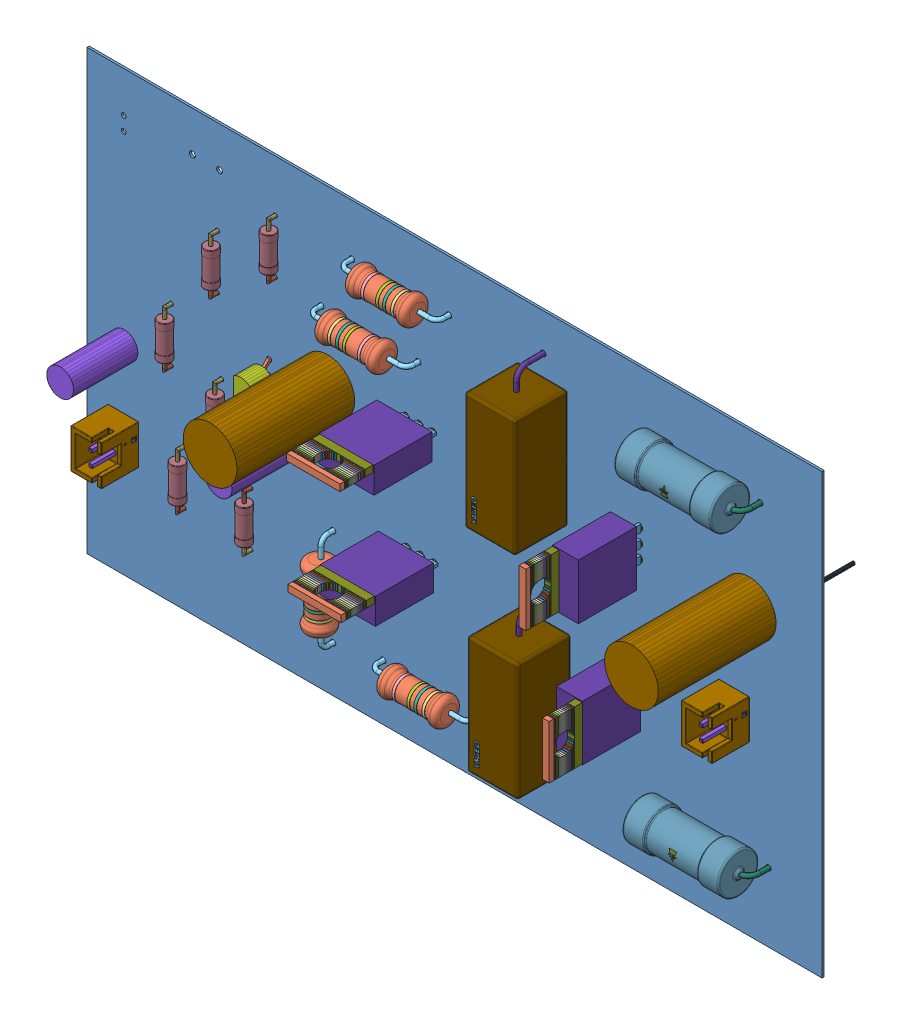
SolidWorks assembly PCB1, configuration Default. Lengths in mm.
Overall size (137.29 81.92 39).
464 component instances, 65 part files, 0 mates.
Components (placement in the parent):
- PCB1.step-1: PCB1.step [Default] at origin size (137.29 81.92 39)
  - Board.step-1: Board.step [Default] at origin size (137.29 81.92 0.41)
    - Open CASCADE STEP translator 6.8 1.1.1.step-1: Open CASCADE STEP translator 6.8 1.1.1.step [Default] at (0 0 -0.4115) size (137.29 81.92 0.41)
  - R61.step-1: R61.step [Default] at origin size (18.91 5.72 7.96)
    - Res_Yageo_KNP100JR-73-22R_eec.step-1: Res_Yageo_KNP100JR-73-22R_eec.step [Default] at (64.389 10.414 0) x (-1 0 0) z (0 0 1) size (18.91 5.72 7.96)
      - 1.step-1: 1.step [Default] at (0 0 2.55) size (11.5 5.1 5.1)
      - 2.step-1: 2.step [Default] at (-3.2931 0 2.55) x (0 0 -1) z (1 0 0) size (4.2 4.2 0.5)
      - 3.step-1: 3.step [Default] at (2.7931 0 2.55) x (0 -0.492137 0.870518) z (-1 0 0) size (4.2 4.2 0.5)
      - 4.step-1: 4.step [Default] at (0 0 -2.55) size (18.91 0.8 5.21)
      - 5.step-1: 5.step [Default] at (-1.7931 0 2.55) x (0 0 -1) z (1 0 0) size (4.2 4.2 0.5)
      - 6.step-1: 6.step [Default] at (0.0069 0 2.55) x (0 -0.017206 0.999852) z (-1 0 0) size (4.2 4.2 0.5)
  - R51.step-1: R51.step [Default] at origin size (18.91 5.72 7.96)
    - Res_Yageo_KNP100JR-73-22R_eec.step-1: Res_Yageo_KNP100JR-73-22R_eec.step [Default] at (52.832 61.976 0) x (1 0 0) z (0 0 1) size (18.91 5.72 7.96)
      - 1.step-1: 1.step [Default] at (0 0 2.55) size (11.5 5.1 5.1)
      - 2.step-1: 2.step [Default] at (-3.2931 0 2.55) x (0 0 -1) z (1 0 0) size (4.2 4.2 0.5)
      - 3.step-1: 3.step [Default] at (2.7931 0 2.55) x (0 -0.492137 0.870518) z (-1 0 0) size (4.2 4.2 0.5)
      - 4.step-1: 4.step [Default] at (0 0 -2.55) size (18.91 0.8 5.21)
      - 5.step-1: 5.step [Default] at (-1.7931 0 2.55) x (0 0 -1) z (1 0 0) size (4.2 4.2 0.5)
      - 6.step-1: 6.step [Default] at (0.0069 0 2.55) x (0 -0.017206 0.999852) z (-1 0 0) size (4.2 4.2 0.5)
  - output.step-1: output.step [Default] at origin size (5.75 7.4 10.4)
    - Conn_JST_B2B-XH-A_LF_SN_eec.step-1: Conn_JST_B2B-XH-A_LF_SN_eec.step [Default] at (120.887 35.072 0) x (0 -1 0) z (0 0 1) size (7.4 5.75 10.4)
      - 1-0.step-1: 1-0.step [Default] at (0 0.025 0) x (-1 0 0) z (0 1 0) size (7.4 10.4 5.75)
        - 1-1.step-1: 1-1.step [Default] at origin size (3.14 10.2 0.64)
        - B2B-XH-A.step-1: B2B-XH-A.step [Default] at origin size (7.4 7 5.75)
        - JST_Logo_adjustable.step-1: JST_Logo_adjustable.step [Default] at (-1.7267 5.5034 2.841) size (0.85 2.3 0.01)
  - input.step-1: input.step [Default] at origin size (5.75 7.4 10.4)
    - Conn_JST_B2B-XH-A_LF_SN_eec.step-1: Conn_JST_B2B-XH-A_LF_SN_eec.step [Default] at (6.841 22.499 0) x (0 -1 0) z (0 0 1) size (7.4 5.75 10.4)
      - 1-0.step-1: 1-0.step [Default] at (0 0.025 0) x (-1 0 0) z (0 1 0) size (7.4 10.4 5.75)
        - 1-1.step-1: 1-1.step [Default] at origin size (3.14 10.2 0.64)
        - B2B-XH-A.step-1: B2B-XH-A.step [Default] at origin size (7.4 7 5.75)
        - JST_Logo_adjustable.step-1: JST_Logo_adjustable.step [Default] at (-1.7267 5.5034 2.841) size (0.85 2.3 0.01)
  - RE.step-1: RE.step [Default] at origin size (2.5 10.6 6.5)
    - Res_Vishay_BC_Components_MRS25000C1101FCT00_eec.step-1: Res_Vishay_BC_Components_MRS25000C1101FCT00_eec.step [Default] at (30.607 20.955 0) x (0 -1 0) z (0 0 1) size (2.05 0.6 5.55)
    - Res_Vishay_BC_Components_MRS25000C1101FCT00_eec-2.step-1: Res_Vishay_BC_Components_MRS25000C1101FCT00_eec-2.step [Default] at (30.607 20.955 0) x (0 -1 0) z (0 0 1) size (2.05 0.6 5.55)
    - Res_Vishay_BC_Components_MRS25000C1101FCT00_eec-3.step-1: Res_Vishay_BC_Components_MRS25000C1101FCT00_eec-3.step [Default] at (30.607 20.955 0) x (0 -1 0) z (0 0 1) size (6.5 2.5 2.5)
  - RC.step-1: RC.step [Default] at origin size (2.5 10.6 6.5)
    - Res_Vishay_BC_Components_MRS25000C1101FCT00_eec.step-1: Res_Vishay_BC_Components_MRS25000C1101FCT00_eec.step [Default] at (35.179 67.31 0) x (0 1 0) z (0 0 1) size (2.05 0.6 5.55)
    - Res_Vishay_BC_Components_MRS25000C1101FCT00_eec-2.step-1: Res_Vishay_BC_Components_MRS25000C1101FCT00_eec-2.step [Default] at (35.179 67.31 0) x (0 1 0) z (0 0 1) size (2.05 0.6 5.55)
    - Res_Vishay_BC_Components_MRS25000C1101FCT00_eec-3.step-1: Res_Vishay_BC_Components_MRS25000C1101FCT00_eec-3.step [Default] at (35.179 67.31 0) x (0 1 0) z (0 0 1) size (6.5 2.5 2.5)
  - R10.step-1: R10.step [Default] at origin size (22.46 7.5 11.5)
    - Res_Vishay_AC05000003909JAC00_eec.step-1: Res_Vishay_AC05000003909JAC00_eec.step [Default] at (116.459 12.827 0) size (22.46 7.5 11.5)
      - AC0500000XXXJAC00.step-1: AC0500000XXXJAC00.step [Default] at (-37 0 3.75) size (18.87 7.5 7.5)
      - 1-4.step-1: 1-4.step [Default] at (0 0 -8) x (1 0 0) z (0 -1 0) size (22.46 8.15 0.8)
      - 2-5.step-1: 2-5.step [Default] at (-37 0 3.75) size (1.63 1.9 3.41)
  - R9.step-1: R9.step [Default] at origin size (22.46 7.5 11.5)
    - Res_Vishay_AC05000003909JAC00_eec.step-1: Res_Vishay_AC05000003909JAC00_eec.step [Default] at (114.935 71.12 0) x (-1 0 0) z (0 0 1) size (22.46 7.5 11.5)
      - AC0500000XXXJAC00.step-1: AC0500000XXXJAC00.step [Default] at (-37 0 3.75) size (18.87 7.5 7.5)
      - 1-4.step-1: 1-4.step [Default] at (0 0 -8) x (1 0 0) z (0 -1 0) size (22.46 8.15 0.8)
      - 2-5.step-1: 2-5.step [Default] at (-37 0 3.75) size (1.63 1.9 3.41)
  - R8.step-1: R8.step [Default] at origin size (9.5 29.91 14)
    - Res_Yageo_SQP500JB-1R2_eec.step-1: Res_Yageo_SQP500JB-1R2_eec.step [Default] at (85.217 60.452 0) x (0 1 0) z (0 0 1) size (29.91 9.5 14)
      - 1-6.step-1: 1-6.step [Default] at origin size (29.91 0.8 9.4)
      - 2-7.step-1: 2-7.step [Default] at origin size (22 9.5 10)
      - Yageo_Logo.step-1: Yageo_Logo.step [Default] at (-8.1443 3.6121 9.991) size (4.52 1.05 0.01)
  - R7.step-1: R7.step [Default] at origin size (9.5 29.91 14)
    - Res_Yageo_SQP500JB-1R2_eec.step-1: Res_Yageo_SQP500JB-1R2_eec.step [Default] at (85.725 21.209 0) x (0 1 0) z (0 0 1) size (29.91 9.5 14)
      - 1-6.step-1: 1-6.step [Default] at origin size (29.91 0.8 9.4)
      - 2-7.step-1: 2-7.step [Default] at origin size (22 9.5 10)
      - Yageo_Logo.step-1: Yageo_Logo.step [Default] at (-8.1443 3.6121 9.991) size (4.52 1.05 0.01)
  - R6.step-1: R6.step [Default] at origin size (5.72 18.91 7.96)
    - Res_Yageo_KNP100JR-73-22R_eec.step-1: Res_Yageo_KNP100JR-73-22R_eec.step [Default] at (45.974 17.653 0) x (0 1 0) z (0 0 1) size (18.91 5.72 7.96)
      - 1.step-1: 1.step [Default] at (0 0 2.55) size (11.5 5.1 5.1)
      - 2.step-1: 2.step [Default] at (-3.2931 0 2.55) x (0 0 -1) z (1 0 0) size (4.2 4.2 0.5)
      - 3.step-1: 3.step [Default] at (2.7931 0 2.55) x (0 -0.492137 0.870518) z (-1 0 0) size (4.2 4.2 0.5)
      - 4.step-1: 4.step [Default] at (0 0 -2.55) size (18.91 0.8 5.21)
      - 5.step-1: 5.step [Default] at (-1.7931 0 2.55) x (0 0 -1) z (1 0 0) size (4.2 4.2 0.5)
      - 6.step-1: 6.step [Default] at (0.0069 0 2.55) x (0 -0.017206 0.999852) z (-1 0 0) size (4.2 4.2 0.5)
  - R5.step-1: R5.step [Default] at origin size (18.91 5.72 7.96)
    - Res_Yageo_KNP100JR-73-22R_eec.step-1: Res_Yageo_KNP100JR-73-22R_eec.step [Default] at (58.547 72.39 0) x (-1 0 0) z (0 0 1) size (18.91 5.72 7.96)
      - 1.step-1: 1.step [Default] at (0 0 2.55) size (11.5 5.1 5.1)
      - 2.step-1: 2.step [Default] at (-3.2931 0 2.55) x (0 0 -1) z (1 0 0) size (4.2 4.2 0.5)
      - 3.step-1: 3.step [Default] at (2.7931 0 2.55) x (0 -0.492137 0.870518) z (-1 0 0) size (4.2 4.2 0.5)
      - 4.step-1: 4.step [Default] at (0 0 -2.55) size (18.91 0.8 5.21)
      - 5.step-1: 5.step [Default] at (-1.7931 0 2.55) x (0 0 -1) z (1 0 0) size (4.2 4.2 0.5)
      - 6.step-1: 6.step [Default] at (0.0069 0 2.55) x (0 -0.017206 0.999852) z (-1 0 0) size (4.2 4.2 0.5)
  - R4.step-1: R4.step [Default] at origin size (2.5 10.6 6.5)
    - Res_Vishay_BC_Components_MRS25000C1101FCT00_eec.step-1: Res_Vishay_BC_Components_MRS25000C1101FCT00_eec.step [Default] at (18.161 21.463 0) x (0 1 0) z (0 0 1) size (2.05 0.6 5.55)
    - Res_Vishay_BC_Components_MRS25000C1101FCT00_eec-2.step-1: Res_Vishay_BC_Components_MRS25000C1101FCT00_eec-2.step [Default] at (18.161 21.463 0) x (0 1 0) z (0 0 1) size (2.05 0.6 5.55)
    - Res_Vishay_BC_Components_MRS25000C1101FCT00_eec-3.step-1: Res_Vishay_BC_Components_MRS25000C1101FCT00_eec-3.step [Default] at (18.161 21.463 0) x (0 1 0) z (0 0 1) size (6.5 2.5 2.5)
  - R3.step-1: R3.step [Default] at origin size (2.5 10.6 6.5)
    - Res_Vishay_BC_Components_MRS25000C1101FCT00_eec.step-1: Res_Vishay_BC_Components_MRS25000C1101FCT00_eec.step [Default] at (25.146 35.814 0) x (0 1 0) z (0 0 1) size (2.05 0.6 5.55)
    - Res_Vishay_BC_Components_MRS25000C1101FCT00_eec-2.step-1: Res_Vishay_BC_Components_MRS25000C1101FCT00_eec-2.step [Default] at (25.146 35.814 0) x (0 1 0) z (0 0 1) size (2.05 0.6 5.55)
    - Res_Vishay_BC_Components_MRS25000C1101FCT00_eec-3.step-1: Res_Vishay_BC_Components_MRS25000C1101FCT00_eec-3.step [Default] at (25.146 35.814 0) x (0 1 0) z (0 0 1) size (6.5 2.5 2.5)
  - R2.step-1: R2.step [Default] at origin size (2.5 10.6 6.5)
    - Res_Vishay_BC_Components_MRS25000C1101FCT00_eec.step-1: Res_Vishay_BC_Components_MRS25000C1101FCT00_eec.step [Default] at (24.384 59.436 0) x (0 1 0) z (0 0 1) size (2.05 0.6 5.55)
    - Res_Vishay_BC_Components_MRS25000C1101FCT00_eec-2.step-1: Res_Vishay_BC_Components_MRS25000C1101FCT00_eec-2.step [Default] at (24.384 59.436 0) x (0 1 0) z (0 0 1) size (2.05 0.6 5.55)
    - Res_Vishay_BC_Components_MRS25000C1101FCT00_eec-3.step-1: Res_Vishay_BC_Components_MRS25000C1101FCT00_eec-3.step [Default] at (24.384 59.436 0) x (0 1 0) z (0 0 1) size (6.5 2.5 2.5)
  - R1.step-1: R1.step [Default] at origin size (2.5 10.6 6.5)
    - Res_Vishay_BC_Components_MRS25000C1101FCT00_eec.step-1: Res_Vishay_BC_Components_MRS25000C1101FCT00_eec.step [Default] at (15.748 43.307 0) x (0 1 0) z (0 0 1) size (2.05 0.6 5.55)
    - Res_Vishay_BC_Components_MRS25000C1101FCT00_eec-2.step-1: Res_Vishay_BC_Components_MRS25000C1101FCT00_eec-2.step [Default] at (15.748 43.307 0) x (0 1 0) z (0 0 1) size (2.05 0.6 5.55)
    - Res_Vishay_BC_Components_MRS25000C1101FCT00_eec-3.step-1: Res_Vishay_BC_Components_MRS25000C1101FCT00_eec-3.step [Default] at (15.748 43.307 0) x (0 1 0) z (0 0 1) size (6.5 2.5 2.5)
  - Q5.step-1: Q5.step [Default] at origin size (4.85 10.3 21.45)
    - 6100337184.step-1: 6100337184.step [Default] at (105.55 30.861 18.98) size (1.25 9.95 0.87)
      - Extruded.step-1: Extruded.step [Default] at origin size (1.25 9.95 0.87)
    - 6100336784.step-1: 6100336784.step [Default] at (105.55 27.411 17.05) size (1.25 3.05 0.38)
      - Extruded-8.step-1: Extruded-8.step [Default] at origin size (1.25 3.05 0.38)
    - 6100336784.step-2: 6100336784.step [Default] at (105.55 34.311 17.05) size (1.25 3.05 0.38)
      - Extruded-8.step-1: Extruded-8.step [Default] at origin size (1.25 3.05 0.38)
    - 6100335504.step-1: 6100335504.step [Default] at (105.55 27.411 16.67) size (1.25 3.05 0.38)
      - Extruded-9.step-1: Extruded-9.step [Default] at origin size (1.25 3.05 0.38)
    - 6100335504.step-2: 6100335504.step [Default] at (105.55 34.311 16.67) size (1.25 3.05 0.38)
      - Extruded-9.step-1: Extruded-9.step [Default] at origin size (1.25 3.05 0.38)
    - 6100342224.step-1: 6100342224.step [Default] at (105.55 27.4295 17.43) size (1.25 3.09 0.36)
      - Extruded-10.step-1: Extruded-10.step [Default] at origin size (1.25 3.09 0.36)
    - 6100342224.step-2: 6100342224.step [Default] at (105.55 34.2925 17.43) size (1.25 3.09 0.36)
      - Extruded-10.step-1: Extruded-10.step [Default] at origin size (1.25 3.09 0.36)
    - 6100331024.step-1: 6100331024.step [Default] at (105.55 27.4295 16.31) size (1.25 3.09 0.37)
      - Extruded-11.step-1: Extruded-11.step [Default] at origin size (1.25 3.09 0.37)
    - 6100331024.step-2: 6100331024.step [Default] at (105.55 34.2925 16.31) size (1.25 3.09 0.37)
      - Extruded-11.step-1: Extruded-11.step [Default] at origin size (1.25 3.09 0.37)
    - 6100330544.step-1: 6100330544.step [Default] at (105.55 27.4843 17.79) size (1.25 3.2 0.33)
      - Extruded-12.step-1: Extruded-12.step [Default] at origin size (1.25 3.2 0.33)
    - 6100330544.step-2: 6100330544.step [Default] at (105.55 34.2377 17.79) size (1.25 3.2 0.33)
      - Extruded-12.step-1: Extruded-12.step [Default] at origin size (1.25 3.2 0.33)
    - 6100330224.step-1: 6100330224.step [Default] at (105.55 27.4843 15.98) size (1.25 3.2 0.34)
      - Extruded-13.step-1: Extruded-13.step [Default] at origin size (1.25 3.2 0.34)
    - 6100330224.step-2: 6100330224.step [Default] at (105.55 34.2377 15.98) size (1.25 3.2 0.34)
      - Extruded-13.step-1: Extruded-13.step [Default] at origin size (1.25 3.2 0.34)
    - 6100325984.step-1: 6100325984.step [Default] at (105.55 27.5732 18.12) size (1.25 3.37 0.3)
      - Extruded-14.step-1: Extruded-14.step [Default] at origin size (1.25 3.37 0.3)
    - 6100325984.step-2: 6100325984.step [Default] at (105.55 34.1488 18.12) size (1.25 3.37 0.3)
      - Extruded-14.step-1: Extruded-14.step [Default] at origin size (1.25 3.37 0.3)
    - 6100325984.step-3: 6100325984.step [Default] at (105.55 27.5732 15.69) size (1.25 3.37 0.3)
      - Extruded-14.step-1: Extruded-14.step [Default] at origin size (1.25 3.37 0.3)
    - 6100325984.step-4: 6100325984.step [Default] at (105.55 34.1488 15.69) size (1.25 3.37 0.3)
      - Extruded-14.step-1: Extruded-14.step [Default] at origin size (1.25 3.37 0.3)
    - 6100325824.step-1: 6100325824.step [Default] at (105.55 27.6929 18.41) size (1.25 3.61 0.25)
      - Extruded-15.step-1: Extruded-15.step [Default] at origin size (1.25 3.61 0.25)
    - 6100325824.step-2: 6100325824.step [Default] at (105.55 34.0291 18.41) size (1.25 3.61 0.25)
      - Extruded-15.step-1: Extruded-15.step [Default] at origin size (1.25 3.61 0.25)
    - 6100326864.step-1: 6100326864.step [Default] at (105.55 27.6929 15.45) size (1.25 3.61 0.24)
      - Extruded-16.step-1: Extruded-16.step [Default] at origin size (1.25 3.61 0.24)
    - 6100326864.step-2: 6100326864.step [Default] at (105.55 34.0291 15.45) size (1.25 3.61 0.24)
      - Extruded-16.step-1: Extruded-16.step [Default] at origin size (1.25 3.61 0.24)
    - 6100326304.step-1: 6100326304.step [Default] at (105.55 27.8388 18.65) size (1.25 3.91 0.18)
      - Extruded-17.step-1: Extruded-17.step [Default] at origin size (1.25 3.91 0.18)
    - 6100326304.step-2: 6100326304.step [Default] at (105.55 33.8832 18.65) size (1.25 3.91 0.18)
      - Extruded-17.step-1: Extruded-17.step [Default] at origin size (1.25 3.91 0.18)
    - 6100326304.step-3: 6100326304.step [Default] at (105.55 27.8388 15.27) size (1.25 3.91 0.18)
      - Extruded-17.step-1: Extruded-17.step [Default] at origin size (1.25 3.91 0.18)
    - 6100326304.step-4: 6100326304.step [Default] at (105.55 33.8832 15.27) size (1.25 3.91 0.18)
      - Extruded-17.step-1: Extruded-17.step [Default] at origin size (1.25 3.91 0.18)
    - 6100326704.step-1: 6100326704.step [Default] at (105.55 28.0052 18.83) size (1.25 4.24 0.11)
      - Extruded-18.step-1: Extruded-18.step [Default] at origin size (1.25 4.24 0.11)
    - 6100326704.step-2: 6100326704.step [Default] at (105.55 33.7168 18.83) size (1.25 4.24 0.11)
      - Extruded-18.step-1: Extruded-18.step [Default] at origin size (1.25 4.24 0.11)
    - 6100327504.step-1: 6100327504.step [Default] at (105.55 28.0052 15.16) size (1.25 4.24 0.12)
      - Extruded-19.step-1: Extruded-19.step [Default] at origin size (1.25 4.24 0.12)
    - 6100327504.step-2: 6100327504.step [Default] at (105.55 33.7168 15.16) size (1.25 4.24 0.12)
      - Extruded-19.step-1: Extruded-19.step [Default] at origin size (1.25 4.24 0.12)
    - 6100327344.step-1: 6100327344.step [Default] at (105.55 28.1857 18.94) size (1.25 4.6 0.04)
      - Extruded-20.step-1: Extruded-20.step [Default] at origin size (1.25 4.6 0.04)
    - 6100327344.step-2: 6100327344.step [Default] at (105.55 33.5363 18.94) size (1.25 4.6 0.04)
      - Extruded-20.step-1: Extruded-20.step [Default] at origin size (1.25 4.6 0.04)
    - 6100327344.step-3: 6100327344.step [Default] at (105.55 28.1857 15.13) size (1.25 4.6 0.04)
      - Extruded-20.step-1: Extruded-20.step [Default] at origin size (1.25 4.6 0.04)
    - 6100327344.step-4: 6100327344.step [Default] at (105.55 33.5363 15.13) size (1.25 4.6 0.04)
      - Extruded-20.step-1: Extruded-20.step [Default] at origin size (1.25 4.6 0.04)
    - 6100330864.step-1: 6100330864.step [Default] at (105.55 30.861 13.65) size (1.25 9.95 1.48)
      - Extruded-21.step-1: Extruded-21.step [Default] at origin size (1.25 9.95 1.48)
    - 6100331424.step-1: 6100331424.step [Default] at (103.75 30.861 2.8) size (4.85 10.3 10.85)
      - Extruded-22.step-1: Extruded-22.step [Default] at origin size (4.85 10.3 10.85)
    - 6100325584.step-1: 6100325584.step [Default] at (103.505 28.321 -1.6) size (0.5 0.78 1.6)
      - Extruded-23.step-1: Extruded-23.step [Default] at origin size (0.5 0.78 1.6)
    - 6138241984.step-1: 6138241984.step [Default] at (103.505 28.321 0) size (0.5 1.34 2.8)
      - Extruded-24.step-1: Extruded-24.step [Default] at origin size (0.5 1.34 2.8)
    - 6100325584.step-2: 6100325584.step [Default] at (103.505 30.861 -1.6) size (0.5 0.78 1.6)
      - Extruded-23.step-1: Extruded-23.step [Default] at origin size (0.5 0.78 1.6)
    - 6138241984.step-2: 6138241984.step [Default] at (103.505 30.861 0) size (0.5 1.34 2.8)
      - Extruded-24.step-1: Extruded-24.step [Default] at origin size (0.5 1.34 2.8)
    - 6100325584.step-3: 6100325584.step [Default] at (103.505 33.401 -1.6) size (0.5 0.78 1.6)
      - Extruded-23.step-1: Extruded-23.step [Default] at origin size (0.5 0.78 1.6)
    - 6138241984.step-3: 6138241984.step [Default] at (103.505 33.401 0) size (0.5 1.34 2.8)
      - Extruded-24.step-1: Extruded-24.step [Default] at origin size (0.5 1.34 2.8)
  - Q4.step-1: Q4.step [Default] at origin size (10.3 4.85 21.45)
    - 6138241504.step-1: 6138241504.step [Default] at (62.357 33.033 18.98) size (9.95 1.25 0.87)
      - Extruded-25.step-1: Extruded-25.step [Default] at origin size (9.95 1.25 0.87)
    - 6138241344.step-1: 6138241344.step [Default] at (65.807 33.033 17.05) size (3.05 1.25 0.38)
      - Extruded-26.step-1: Extruded-26.step [Default] at origin size (3.05 1.25 0.38)
    - 6138241344.step-2: 6138241344.step [Default] at (58.907 33.033 17.05) size (3.05 1.25 0.38)
      - Extruded-26.step-1: Extruded-26.step [Default] at origin size (3.05 1.25 0.38)
    - 6138241104.step-1: 6138241104.step [Default] at (65.807 33.033 16.67) size (3.05 1.25 0.38)
      - Extruded-27.step-1: Extruded-27.step [Default] at origin size (3.05 1.25 0.38)
    - 6138241104.step-2: 6138241104.step [Default] at (58.907 33.033 16.67) size (3.05 1.25 0.38)
      - Extruded-27.step-1: Extruded-27.step [Default] at origin size (3.05 1.25 0.38)
    - 6138240864.step-1: 6138240864.step [Default] at (65.7885 33.033 17.43) size (3.09 1.25 0.36)
      - Extruded-28.step-1: Extruded-28.step [Default] at origin size (3.09 1.25 0.36)
    - 6138240864.step-2: 6138240864.step [Default] at (58.9255 33.033 17.43) size (3.09 1.25 0.36)
      - Extruded-28.step-1: Extruded-28.step [Default] at origin size (3.09 1.25 0.36)
    - 6138240624.step-1: 6138240624.step [Default] at (65.7885 33.033 16.31) size (3.09 1.25 0.37)
      - Extruded-29.step-1: Extruded-29.step [Default] at origin size (3.09 1.25 0.37)
    - 6138240624.step-2: 6138240624.step [Default] at (58.9255 33.033 16.31) size (3.09 1.25 0.37)
      - Extruded-29.step-1: Extruded-29.step [Default] at origin size (3.09 1.25 0.37)
    - 6138240384.step-1: 6138240384.step [Default] at (65.7337 33.033 17.79) size (3.2 1.25 0.33)
      - Extruded-30.step-1: Extruded-30.step [Default] at origin size (3.2 1.25 0.33)
    - 6138240384.step-2: 6138240384.step [Default] at (58.9803 33.033 17.79) size (3.2 1.25 0.33)
      - Extruded-30.step-1: Extruded-30.step [Default] at origin size (3.2 1.25 0.33)
    - 6138240144.step-1: 6138240144.step [Default] at (65.7337 33.033 15.98) size (3.2 1.25 0.34)
      - Extruded-31.step-1: Extruded-31.step [Default] at origin size (3.2 1.25 0.34)
    - 6138240144.step-2: 6138240144.step [Default] at (58.9803 33.033 15.98) size (3.2 1.25 0.34)
      - Extruded-31.step-1: Extruded-31.step [Default] at origin size (3.2 1.25 0.34)
    - 6138239904.step-1: 6138239904.step [Default] at (65.6448 33.033 18.12) size (3.37 1.25 0.3)
      - Extruded-32.step-1: Extruded-32.step [Default] at origin size (3.37 1.25 0.3)
    - 6138239904.step-2: 6138239904.step [Default] at (59.0692 33.033 18.12) size (3.37 1.25 0.3)
      - Extruded-32.step-1: Extruded-32.step [Default] at origin size (3.37 1.25 0.3)
    - 6138239904.step-3: 6138239904.step [Default] at (65.6448 33.033 15.69) size (3.37 1.25 0.3)
      - Extruded-32.step-1: Extruded-32.step [Default] at origin size (3.37 1.25 0.3)
    - 6138239904.step-4: 6138239904.step [Default] at (59.0692 33.033 15.69) size (3.37 1.25 0.3)
      - Extruded-32.step-1: Extruded-32.step [Default] at origin size (3.37 1.25 0.3)
    - 6138239504.step-1: 6138239504.step [Default] at (65.5251 33.033 18.41) size (3.61 1.25 0.25)
      - Extruded-33.step-1: Extruded-33.step [Default] at origin size (3.61 1.25 0.25)
    - 6138239504.step-2: 6138239504.step [Default] at (59.1889 33.033 18.41) size (3.61 1.25 0.25)
      - Extruded-33.step-1: Extruded-33.step [Default] at origin size (3.61 1.25 0.25)
    - 6138239264.step-1: 6138239264.step [Default] at (65.5251 33.033 15.45) size (3.61 1.25 0.24)
      - Extruded-34.step-1: Extruded-34.step [Default] at origin size (3.61 1.25 0.24)
    - 6138239264.step-2: 6138239264.step [Default] at (59.1889 33.033 15.45) size (3.61 1.25 0.24)
      - Extruded-34.step-1: Extruded-34.step [Default] at origin size (3.61 1.25 0.24)
    - 6138239024.step-1: 6138239024.step [Default] at (65.3792 33.033 18.65) size (3.91 1.25 0.18)
      - Extruded-35.step-1: Extruded-35.step [Default] at origin size (3.91 1.25 0.18)
    - 6138239024.step-2: 6138239024.step [Default] at (59.3348 33.033 18.65) size (3.91 1.25 0.18)
      - Extruded-35.step-1: Extruded-35.step [Default] at origin size (3.91 1.25 0.18)
    - 6138239024.step-3: 6138239024.step [Default] at (65.3792 33.033 15.27) size (3.91 1.25 0.18)
      - Extruded-35.step-1: Extruded-35.step [Default] at origin size (3.91 1.25 0.18)
    - 6138239024.step-4: 6138239024.step [Default] at (59.3348 33.033 15.27) size (3.91 1.25 0.18)
      - Extruded-35.step-1: Extruded-35.step [Default] at origin size (3.91 1.25 0.18)
    - 6138238624.step-1: 6138238624.step [Default] at (65.2128 33.033 18.83) size (4.24 1.25 0.11)
      - Extruded-36.step-1: Extruded-36.step [Default] at origin size (4.24 1.25 0.11)
    - 6138238624.step-2: 6138238624.step [Default] at (59.5012 33.033 18.83) size (4.24 1.25 0.11)
      - Extruded-36.step-1: Extruded-36.step [Default] at origin size (4.24 1.25 0.11)
    - 6138238384.step-1: 6138238384.step [Default] at (65.2128 33.033 15.16) size (4.24 1.25 0.12)
      - Extruded-37.step-1: Extruded-37.step [Default] at origin size (4.24 1.25 0.12)
    - 6138238384.step-2: 6138238384.step [Default] at (59.5012 33.033 15.16) size (4.24 1.25 0.12)
      - Extruded-37.step-1: Extruded-37.step [Default] at origin size (4.24 1.25 0.12)
    - 6138238144.step-1: 6138238144.step [Default] at (65.0323 33.033 18.94) size (4.6 1.25 0.04)
      - Extruded-38.step-1: Extruded-38.step [Default] at origin size (4.6 1.25 0.04)
    - 6138238144.step-2: 6138238144.step [Default] at (59.6817 33.033 18.94) size (4.6 1.25 0.04)
      - Extruded-38.step-1: Extruded-38.step [Default] at origin size (4.6 1.25 0.04)
    - 6138238144.step-3: 6138238144.step [Default] at (65.0323 33.033 15.13) size (4.6 1.25 0.04)
      - Extruded-38.step-1: Extruded-38.step [Default] at origin size (4.6 1.25 0.04)
    - 6138238144.step-4: 6138238144.step [Default] at (59.6817 33.033 15.13) size (4.6 1.25 0.04)
      - Extruded-38.step-1: Extruded-38.step [Default] at origin size (4.6 1.25 0.04)
    - 6138237744.step-1: 6138237744.step [Default] at (62.357 33.033 13.65) size (9.95 1.25 1.48)
      - Extruded-39.step-1: Extruded-39.step [Default] at origin size (9.95 1.25 1.48)
    - 6138237584.step-1: 6138237584.step [Default] at (62.357 31.233 2.8) size (10.3 4.85 10.85)
      - Extruded-40.step-1: Extruded-40.step [Default] at origin size (10.3 4.85 10.85)
    - 6138237424.step-1: 6138237424.step [Default] at (64.897 30.988 -1.6) size (0.78 0.5 1.6)
      - Extruded-41.step-1: Extruded-41.step [Default] at origin size (0.78 0.5 1.6)
    - 6138237264.step-1: 6138237264.step [Default] at (64.897 30.988 0) size (1.34 0.5 2.8)
      - Extruded-42.step-1: Extruded-42.step [Default] at origin size (1.34 0.5 2.8)
    - 6138237424.step-2: 6138237424.step [Default] at (62.357 30.988 -1.6) size (0.78 0.5 1.6)
      - Extruded-41.step-1: Extruded-41.step [Default] at origin size (0.78 0.5 1.6)
    - 6138237264.step-2: 6138237264.step [Default] at (62.357 30.988 0) size (1.34 0.5 2.8)
      - Extruded-42.step-1: Extruded-42.step [Default] at origin size (1.34 0.5 2.8)
    - 6138237424.step-3: 6138237424.step [Default] at (59.817 30.988 -1.6) size (0.78 0.5 1.6)
      - Extruded-41.step-1: Extruded-41.step [Default] at origin size (0.78 0.5 1.6)
    - 6138237264.step-3: 6138237264.step [Default] at (59.817 30.988 0) size (1.34 0.5 2.8)
      - Extruded-42.step-1: Extruded-42.step [Default] at origin size (1.34 0.5 2.8)
  - Q3.step-1: Q3.step [Default] at origin size (3.69 5.68 14.04)
    - PCB3.step-1: PCB3.step [Default] at (34.0361 45.8469 4) x (0 -1 0) z (0 0 1) size (5.68 0.46 12.71)
      - Free-Models.step-1: Free-Models.step [Default] at origin size (5.68 0.46 12.71)
        - PCB1.step-1: PCB1.step [Default] at (-1.2706 -0.1276 0) x (1 0 0) z (0 -1 0) size (1.81 12.71 0.46)
          - Free-Models-1.step-1: Free-Models-1.step [Default] at origin size (1.81 12.71 0.46)
            - 523779104.step-1: 523779104.step [Default] at (-0.665 -6.35 -0.35) size (1.81 12.71 0.46)
              - Extruded-43.step-1: Extruded-43.step [Default] at origin size (1.81 12.71 0.46)
          - Board-44.step-1: Board-44.step [Default] at (0 0 -0.2083) size (0.27 0.27 0.21)
        - PCB2.step-1: PCB2.step [Default] at (0.0004 -0.1275 0) x (1 0 0) z (0 -1 0) size (0.47 12.7 0.45)
          - Free-Models-2.step-1: Free-Models-2.step [Default] at origin size (0.47 12.7 0.45)
            - 790454240.step-1: 790454240.step [Default] at (0 -6.35 -0.35) size (0.47 12.7 0.45)
              - Extruded-45.step-1: Extruded-45.step [Default] at origin size (0.47 12.7 0.45)
          - Board-46.step-1: Board-46.step [Default] at (0 0 -0.2083) size (0.27 0.27 0.21)
        - PCB1.step-2: PCB1.step [Default] at (1.2705 0.1276 0) x (-1 0 0) z (0 1 0) size (1.81 12.71 0.46)
          - Free-Models-1.step-1: Free-Models-1.step [Default] at origin size (1.81 12.71 0.46)
            - 523779104.step-1: 523779104.step [Default] at (-0.665 -6.35 -0.35) size (1.81 12.71 0.46)
              - Extruded-43.step-1: Extruded-43.step [Default] at origin size (1.81 12.71 0.46)
          - Board-44.step-1: Board-44.step [Default] at (0 0 -0.2083) size (0.27 0.27 0.21)
      - Board-47.step-1: Board-47.step [Default] at (0 0 -0.2083) size (0.31 0.31 0.21)
    - 6100335024.step-1: 6100335024.step [Default] at (34.5437 45.847 1.5) size (3.69 4.72 3.83)
      - Extruded-48.step-1: Extruded-48.step [Default] at origin size (3.69 4.72 3.83)
  - Q2.step-1: Q2.step [Default] at origin size (10.3 4.85 21.45)
    - 6138241504.step-1: 6138241504.step [Default] at (62.103 54.115 18.98) size (9.95 1.25 0.87)
      - Extruded-25.step-1: Extruded-25.step [Default] at origin size (9.95 1.25 0.87)
    - 6138241344.step-1: 6138241344.step [Default] at (65.553 54.115 17.05) size (3.05 1.25 0.38)
      - Extruded-26.step-1: Extruded-26.step [Default] at origin size (3.05 1.25 0.38)
    - 6138241344.step-2: 6138241344.step [Default] at (58.653 54.115 17.05) size (3.05 1.25 0.38)
      - Extruded-26.step-1: Extruded-26.step [Default] at origin size (3.05 1.25 0.38)
    - 6138241104.step-1: 6138241104.step [Default] at (65.553 54.115 16.67) size (3.05 1.25 0.38)
      - Extruded-27.step-1: Extruded-27.step [Default] at origin size (3.05 1.25 0.38)
    - 6138241104.step-2: 6138241104.step [Default] at (58.653 54.115 16.67) size (3.05 1.25 0.38)
      - Extruded-27.step-1: Extruded-27.step [Default] at origin size (3.05 1.25 0.38)
    - 6138240864.step-1: 6138240864.step [Default] at (65.5345 54.115 17.43) size (3.09 1.25 0.36)
      - Extruded-28.step-1: Extruded-28.step [Default] at origin size (3.09 1.25 0.36)
    - 6138240864.step-2: 6138240864.step [Default] at (58.6715 54.115 17.43) size (3.09 1.25 0.36)
      - Extruded-28.step-1: Extruded-28.step [Default] at origin size (3.09 1.25 0.36)
    - 6138240624.step-1: 6138240624.step [Default] at (65.5345 54.115 16.31) size (3.09 1.25 0.37)
      - Extruded-29.step-1: Extruded-29.step [Default] at origin size (3.09 1.25 0.37)
    - 6138240624.step-2: 6138240624.step [Default] at (58.6715 54.115 16.31) size (3.09 1.25 0.37)
      - Extruded-29.step-1: Extruded-29.step [Default] at origin size (3.09 1.25 0.37)
    - 6138240384.step-1: 6138240384.step [Default] at (65.4797 54.115 17.79) size (3.2 1.25 0.33)
      - Extruded-30.step-1: Extruded-30.step [Default] at origin size (3.2 1.25 0.33)
    - 6138240384.step-2: 6138240384.step [Default] at (58.7263 54.115 17.79) size (3.2 1.25 0.33)
      - Extruded-30.step-1: Extruded-30.step [Default] at origin size (3.2 1.25 0.33)
    - 6138240144.step-1: 6138240144.step [Default] at (65.4797 54.115 15.98) size (3.2 1.25 0.34)
      - Extruded-31.step-1: Extruded-31.step [Default] at origin size (3.2 1.25 0.34)
    - 6138240144.step-2: 6138240144.step [Default] at (58.7263 54.115 15.98) size (3.2 1.25 0.34)
      - Extruded-31.step-1: Extruded-31.step [Default] at origin size (3.2 1.25 0.34)
    - 6138239904.step-1: 6138239904.step [Default] at (65.3908 54.115 18.12) size (3.37 1.25 0.3)
      - Extruded-32.step-1: Extruded-32.step [Default] at origin size (3.37 1.25 0.3)
    - 6138239904.step-2: 6138239904.step [Default] at (58.8152 54.115 18.12) size (3.37 1.25 0.3)
      - Extruded-32.step-1: Extruded-32.step [Default] at origin size (3.37 1.25 0.3)
    - 6138239904.step-3: 6138239904.step [Default] at (65.3908 54.115 15.69) size (3.37 1.25 0.3)
      - Extruded-32.step-1: Extruded-32.step [Default] at origin size (3.37 1.25 0.3)
    - 6138239904.step-4: 6138239904.step [Default] at (58.8152 54.115 15.69) size (3.37 1.25 0.3)
      - Extruded-32.step-1: Extruded-32.step [Default] at origin size (3.37 1.25 0.3)
    - 6138239504.step-1: 6138239504.step [Default] at (65.2711 54.115 18.41) size (3.61 1.25 0.25)
      - Extruded-33.step-1: Extruded-33.step [Default] at origin size (3.61 1.25 0.25)
    - 6138239504.step-2: 6138239504.step [Default] at (58.9349 54.115 18.41) size (3.61 1.25 0.25)
      - Extruded-33.step-1: Extruded-33.step [Default] at origin size (3.61 1.25 0.25)
    - 6138239264.step-1: 6138239264.step [Default] at (65.2711 54.115 15.45) size (3.61 1.25 0.24)
      - Extruded-34.step-1: Extruded-34.step [Default] at origin size (3.61 1.25 0.24)
    - 6138239264.step-2: 6138239264.step [Default] at (58.9349 54.115 15.45) size (3.61 1.25 0.24)
      - Extruded-34.step-1: Extruded-34.step [Default] at origin size (3.61 1.25 0.24)
    - 6138239024.step-1: 6138239024.step [Default] at (65.1252 54.115 18.65) size (3.91 1.25 0.18)
      - Extruded-35.step-1: Extruded-35.step [Default] at origin size (3.91 1.25 0.18)
    - 6138239024.step-2: 6138239024.step [Default] at (59.0808 54.115 18.65) size (3.91 1.25 0.18)
      - Extruded-35.step-1: Extruded-35.step [Default] at origin size (3.91 1.25 0.18)
    - 6138239024.step-3: 6138239024.step [Default] at (65.1252 54.115 15.27) size (3.91 1.25 0.18)
      - Extruded-35.step-1: Extruded-35.step [Default] at origin size (3.91 1.25 0.18)
    - 6138239024.step-4: 6138239024.step [Default] at (59.0808 54.115 15.27) size (3.91 1.25 0.18)
      - Extruded-35.step-1: Extruded-35.step [Default] at origin size (3.91 1.25 0.18)
    - 6138238624.step-1: 6138238624.step [Default] at (64.9588 54.115 18.83) size (4.24 1.25 0.11)
      - Extruded-36.step-1: Extruded-36.step [Default] at origin size (4.24 1.25 0.11)
    - 6138238624.step-2: 6138238624.step [Default] at (59.2472 54.115 18.83) size (4.24 1.25 0.11)
      - Extruded-36.step-1: Extruded-36.step [Default] at origin size (4.24 1.25 0.11)
    - 6138238384.step-1: 6138238384.step [Default] at (64.9588 54.115 15.16) size (4.24 1.25 0.12)
      - Extruded-37.step-1: Extruded-37.step [Default] at origin size (4.24 1.25 0.12)
    - 6138238384.step-2: 6138238384.step [Default] at (59.2472 54.115 15.16) size (4.24 1.25 0.12)
      - Extruded-37.step-1: Extruded-37.step [Default] at origin size (4.24 1.25 0.12)
    - 6138238144.step-1: 6138238144.step [Default] at (64.7783 54.115 18.94) size (4.6 1.25 0.04)
      - Extruded-38.step-1: Extruded-38.step [Default] at origin size (4.6 1.25 0.04)
    - 6138238144.step-2: 6138238144.step [Default] at (59.4277 54.115 18.94) size (4.6 1.25 0.04)
      - Extruded-38.step-1: Extruded-38.step [Default] at origin size (4.6 1.25 0.04)
    - 6138238144.step-3: 6138238144.step [Default] at (64.7783 54.115 15.13) size (4.6 1.25 0.04)
      - Extruded-38.step-1: Extruded-38.step [Default] at origin size (4.6 1.25 0.04)
    - 6138238144.step-4: 6138238144.step [Default] at (59.4277 54.115 15.13) size (4.6 1.25 0.04)
      - Extruded-38.step-1: Extruded-38.step [Default] at origin size (4.6 1.25 0.04)
    - 6138237744.step-1: 6138237744.step [Default] at (62.103 54.115 13.65) size (9.95 1.25 1.48)
      - Extruded-39.step-1: Extruded-39.step [Default] at origin size (9.95 1.25 1.48)
    - 6138237584.step-1: 6138237584.step [Default] at (62.103 52.315 2.8) size (10.3 4.85 10.85)
      - Extruded-40.step-1: Extruded-40.step [Default] at origin size (10.3 4.85 10.85)
    - 6138237424.step-1: 6138237424.step [Default] at (64.643 52.07 -1.6) size (0.78 0.5 1.6)
      - Extruded-41.step-1: Extruded-41.step [Default] at origin size (0.78 0.5 1.6)
    - 6138237264.step-1: 6138237264.step [Default] at (64.643 52.07 0) size (1.34 0.5 2.8)
      - Extruded-42.step-1: Extruded-42.step [Default] at origin size (1.34 0.5 2.8)
    - 6138237424.step-2: 6138237424.step [Default] at (62.103 52.07 -1.6) size (0.78 0.5 1.6)
      - Extruded-41.step-1: Extruded-41.step [Default] at origin size (0.78 0.5 1.6)
    - 6138237264.step-2: 6138237264.step [Default] at (62.103 52.07 0) size (1.34 0.5 2.8)
      - Extruded-42.step-1: Extruded-42.step [Default] at origin size (1.34 0.5 2.8)
    - 6138237424.step-3: 6138237424.step [Default] at (59.563 52.07 -1.6) size (0.78 0.5 1.6)
      - Extruded-41.step-1: Extruded-41.step [Default] at origin size (0.78 0.5 1.6)
    - 6138237264.step-3: 6138237264.step [Default] at (59.563 52.07 0) size (1.34 0.5 2.8)
      - Extruded-42.step-1: Extruded-42.step [Default] at origin size (1.34 0.5 2.8)
  - Q1.step-1: Q1.step [Default] at origin size (4.85 10.3 21.45)
    - 6100337184.step-1: 6100337184.step [Default] at (101.206 53.34 18.98) size (1.25 9.95 0.87)
      - Extruded.step-1: Extruded.step [Default] at origin size (1.25 9.95 0.87)
    - 6100336784.step-1: 6100336784.step [Default] at (101.206 56.79 17.05) size (1.25 3.05 0.38)
      - Extruded-8.step-1: Extruded-8.step [Default] at origin size (1.25 3.05 0.38)
    - 6100336784.step-2: 6100336784.step [Default] at (101.206 49.89 17.05) size (1.25 3.05 0.38)
      - Extruded-8.step-1: Extruded-8.step [Default] at origin size (1.25 3.05 0.38)
    - 6100335504.step-1: 6100335504.step [Default] at (101.206 56.79 16.67) size (1.25 3.05 0.38)
      - Extruded-9.step-1: Extruded-9.step [Default] at origin size (1.25 3.05 0.38)
    - 6100335504.step-2: 6100335504.step [Default] at (101.206 49.89 16.67) size (1.25 3.05 0.38)
      - Extruded-9.step-1: Extruded-9.step [Default] at origin size (1.25 3.05 0.38)
    - 6100342224.step-1: 6100342224.step [Default] at (101.206 56.7715 17.43) size (1.25 3.09 0.36)
      - Extruded-10.step-1: Extruded-10.step [Default] at origin size (1.25 3.09 0.36)
    - 6100342224.step-2: 6100342224.step [Default] at (101.206 49.9085 17.43) size (1.25 3.09 0.36)
      - Extruded-10.step-1: Extruded-10.step [Default] at origin size (1.25 3.09 0.36)
    - 6100331024.step-1: 6100331024.step [Default] at (101.206 56.7715 16.31) size (1.25 3.09 0.37)
      - Extruded-11.step-1: Extruded-11.step [Default] at origin size (1.25 3.09 0.37)
    - 6100331024.step-2: 6100331024.step [Default] at (101.206 49.9085 16.31) size (1.25 3.09 0.37)
      - Extruded-11.step-1: Extruded-11.step [Default] at origin size (1.25 3.09 0.37)
    - 6100330544.step-1: 6100330544.step [Default] at (101.206 56.7167 17.79) size (1.25 3.2 0.33)
      - Extruded-12.step-1: Extruded-12.step [Default] at origin size (1.25 3.2 0.33)
    - 6100330544.step-2: 6100330544.step [Default] at (101.206 49.9633 17.79) size (1.25 3.2 0.33)
      - Extruded-12.step-1: Extruded-12.step [Default] at origin size (1.25 3.2 0.33)
    - 6100330224.step-1: 6100330224.step [Default] at (101.206 56.7167 15.98) size (1.25 3.2 0.34)
      - Extruded-13.step-1: Extruded-13.step [Default] at origin size (1.25 3.2 0.34)
    - 6100330224.step-2: 6100330224.step [Default] at (101.206 49.9633 15.98) size (1.25 3.2 0.34)
      - Extruded-13.step-1: Extruded-13.step [Default] at origin size (1.25 3.2 0.34)
    - 6100325984.step-1: 6100325984.step [Default] at (101.206 56.6278 18.12) size (1.25 3.37 0.3)
      - Extruded-14.step-1: Extruded-14.step [Default] at origin size (1.25 3.37 0.3)
    - 6100325984.step-2: 6100325984.step [Default] at (101.206 50.0522 18.12) size (1.25 3.37 0.3)
      - Extruded-14.step-1: Extruded-14.step [Default] at origin size (1.25 3.37 0.3)
    - 6100325984.step-3: 6100325984.step [Default] at (101.206 56.6278 15.69) size (1.25 3.37 0.3)
      - Extruded-14.step-1: Extruded-14.step [Default] at origin size (1.25 3.37 0.3)
    - 6100325984.step-4: 6100325984.step [Default] at (101.206 50.0522 15.69) size (1.25 3.37 0.3)
      - Extruded-14.step-1: Extruded-14.step [Default] at origin size (1.25 3.37 0.3)
    - 6100325824.step-1: 6100325824.step [Default] at (101.206 56.5081 18.41) size (1.25 3.61 0.25)
      - Extruded-15.step-1: Extruded-15.step [Default] at origin size (1.25 3.61 0.25)
    - 6100325824.step-2: 6100325824.step [Default] at (101.206 50.1719 18.41) size (1.25 3.61 0.25)
      - Extruded-15.step-1: Extruded-15.step [Default] at origin size (1.25 3.61 0.25)
    - 6100326864.step-1: 6100326864.step [Default] at (101.206 56.5081 15.45) size (1.25 3.61 0.24)
      - Extruded-16.step-1: Extruded-16.step [Default] at origin size (1.25 3.61 0.24)
    - 6100326864.step-2: 6100326864.step [Default] at (101.206 50.1719 15.45) size (1.25 3.61 0.24)
      - Extruded-16.step-1: Extruded-16.step [Default] at origin size (1.25 3.61 0.24)
    - 6100326304.step-1: 6100326304.step [Default] at (101.206 56.3622 18.65) size (1.25 3.91 0.18)
      - Extruded-17.step-1: Extruded-17.step [Default] at origin size (1.25 3.91 0.18)
    - 6100326304.step-2: 6100326304.step [Default] at (101.206 50.3178 18.65) size (1.25 3.91 0.18)
      - Extruded-17.step-1: Extruded-17.step [Default] at origin size (1.25 3.91 0.18)
    - 6100326304.step-3: 6100326304.step [Default] at (101.206 56.3622 15.27) size (1.25 3.91 0.18)
      - Extruded-17.step-1: Extruded-17.step [Default] at origin size (1.25 3.91 0.18)
    - 6100326304.step-4: 6100326304.step [Default] at (101.206 50.3178 15.27) size (1.25 3.91 0.18)
      - Extruded-17.step-1: Extruded-17.step [Default] at origin size (1.25 3.91 0.18)
    - 6100326704.step-1: 6100326704.step [Default] at (101.206 56.1958 18.83) size (1.25 4.24 0.11)
      - Extruded-18.step-1: Extruded-18.step [Default] at origin size (1.25 4.24 0.11)
    - 6100326704.step-2: 6100326704.step [Default] at (101.206 50.4842 18.83) size (1.25 4.24 0.11)
      - Extruded-18.step-1: Extruded-18.step [Default] at origin size (1.25 4.24 0.11)
    - 6100327504.step-1: 6100327504.step [Default] at (101.206 56.1958 15.16) size (1.25 4.24 0.12)
      - Extruded-19.step-1: Extruded-19.step [Default] at origin size (1.25 4.24 0.12)
    - 6100327504.step-2: 6100327504.step [Default] at (101.206 50.4842 15.16) size (1.25 4.24 0.12)
      - Extruded-19.step-1: Extruded-19.step [Default] at origin size (1.25 4.24 0.12)
    - 6100327344.step-1: 6100327344.step [Default] at (101.206 56.0153 18.94) size (1.25 4.6 0.04)
      - Extruded-20.step-1: Extruded-20.step [Default] at origin size (1.25 4.6 0.04)
    - 6100327344.step-2: 6100327344.step [Default] at (101.206 50.6647 18.94) size (1.25 4.6 0.04)
      - Extruded-20.step-1: Extruded-20.step [Default] at origin size (1.25 4.6 0.04)
    - 6100327344.step-3: 6100327344.step [Default] at (101.206 56.0153 15.13) size (1.25 4.6 0.04)
      - Extruded-20.step-1: Extruded-20.step [Default] at origin size (1.25 4.6 0.04)
    - 6100327344.step-4: 6100327344.step [Default] at (101.206 50.6647 15.13) size (1.25 4.6 0.04)
      - Extruded-20.step-1: Extruded-20.step [Default] at origin size (1.25 4.6 0.04)
    - 6100330864.step-1: 6100330864.step [Default] at (101.206 53.34 13.65) size (1.25 9.95 1.48)
      - Extruded-21.step-1: Extruded-21.step [Default] at origin size (1.25 9.95 1.48)
    - 6100331424.step-1: 6100331424.step [Default] at (103.006 53.34 2.8) size (4.85 10.3 10.85)
      - Extruded-22.step-1: Extruded-22.step [Default] at origin size (4.85 10.3 10.85)
    - 6100325584.step-1: 6100325584.step [Default] at (103.251 55.88 -1.6) size (0.5 0.78 1.6)
      - Extruded-23.step-1: Extruded-23.step [Default] at origin size (0.5 0.78 1.6)
    - 6138241984.step-1: 6138241984.step [Default] at (103.251 55.88 0) size (0.5 1.34 2.8)
      - Extruded-24.step-1: Extruded-24.step [Default] at origin size (0.5 1.34 2.8)
    - 6100325584.step-2: 6100325584.step [Default] at (103.251 53.34 -1.6) size (0.5 0.78 1.6)
      - Extruded-23.step-1: Extruded-23.step [Default] at origin size (0.5 0.78 1.6)
    - 6138241984.step-2: 6138241984.step [Default] at (103.251 53.34 0) size (0.5 1.34 2.8)
      - Extruded-24.step-1: Extruded-24.step [Default] at origin size (0.5 1.34 2.8)
    - 6100325584.step-3: 6100325584.step [Default] at (103.251 50.8 -1.6) size (0.5 0.78 1.6)
      - Extruded-23.step-1: Extruded-23.step [Default] at origin size (0.5 0.78 1.6)
    - 6138241984.step-3: 6138241984.step [Default] at (103.251 50.8 0) size (0.5 1.34 2.8)
      - Extruded-24.step-1: Extruded-24.step [Default] at origin size (0.5 1.34 2.8)
  - C4.step-1: C4.step [Default] at origin size (5 5 12)
    - 6100339584.step-1: 6100339584.step [Default] at (36.576 35.941 0) size (5 5 12)
      - Extruded-49.step-1: Extruded-49.step [Default] at origin size (5 5 12)
  - C3.step-1: C3.step [Default] at origin size (10 10 39)
    - 6100340144.step-1: 6100340144.step [Default] at (123.698 53.086 0) size (10 10 22)
      - Extruded-50.step-1: Extruded-50.step [Default] at origin size (10 10 22)
    - 6100332544.step-1: 6100332544.step [Default] at (126.198 53.086 -17) size (0.6 0.6 17)
      - Extruded-51.step-1: Extruded-51.step [Default] at origin size (0.6 0.6 17)
    - 6100341584.step-1: 6100341584.step [Default] at (121.1981 53.0859 -14) size (0.6 0.6 14)
      - Extruded-52.step-1: Extruded-52.step [Default] at origin size (0.6 0.6 14)
  - C2.step-1: C2.step [Default] at origin size (5 5 12)
    - 6100339584.step-1: 6100339584.step [Default] at (6.985 37.211 0) size (5 5 12)
      - Extruded-49.step-1: Extruded-49.step [Default] at origin size (5 5 12)
  - C1.step-1: C1.step [Default] at origin size (10 10 39)
    - 6100340144.step-1: 6100340144.step [Default] at (44.998 49.657 0) size (10 10 22)
      - Extruded-50.step-1: Extruded-50.step [Default] at origin size (10 10 22)
    - 6100332544.step-1: 6100332544.step [Default] at (42.498 49.657 -17) size (0.6 0.6 17)
      - Extruded-51.step-1: Extruded-51.step [Default] at origin size (0.6 0.6 17)
    - 6100341584.step-1: 6100341584.step [Default] at (47.4979 49.6571 -14) size (0.6 0.6 14)
      - Extruded-52.step-1: Extruded-52.step [Default] at origin size (0.6 0.6 14)
